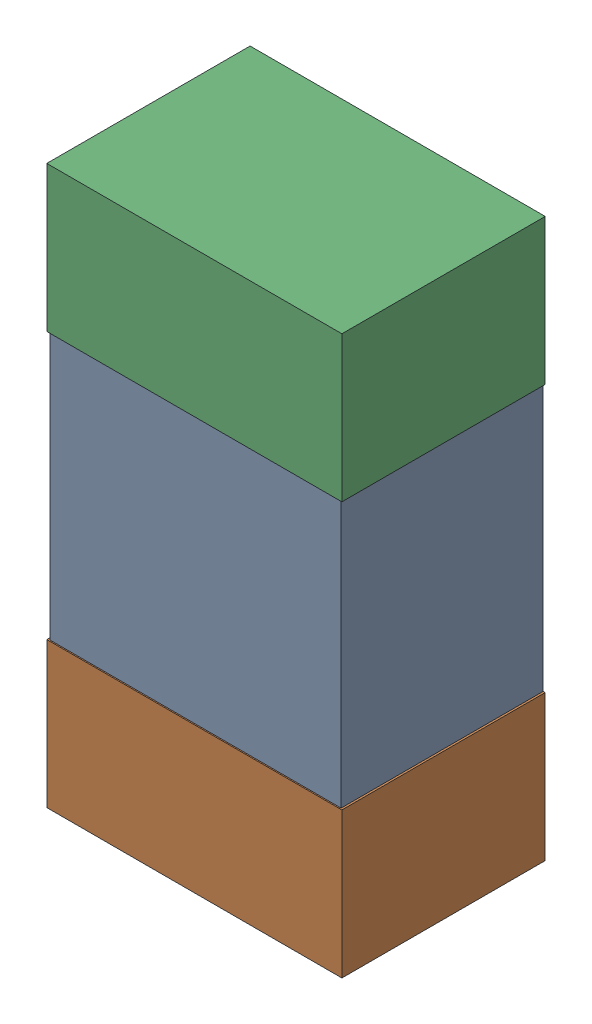
SolidWorks assembly CoutSlByp2Kanaloa_v2.0.0_Power, configuration Default. Lengths in mm.
Overall size (1.83 3.45 1.26).
6 component instances, 2 part files, 0 mates.
Components (placement in the parent):
- 378154176-1: 378154176 [Default] at (86.575 51.775 0) size (1.8 3.4 1.25)
  - Extruded_12-1: Extruded_12 [Default] at origin size (1.8 3.4 1.25)
- 378154304-1: 378154304 [Default] at (86.575 50.5 0) size (1.83 0.9 1.26)
  - Extruded_13-1: Extruded_13 [Default] at origin size (1.83 0.9 1.26)
- 378154304-2: 378154304 [Default] at (86.575 53.05 0) size (1.83 0.9 1.26)
  - Extruded_13-1: Extruded_13 [Default] at origin size (1.83 0.9 1.26)
